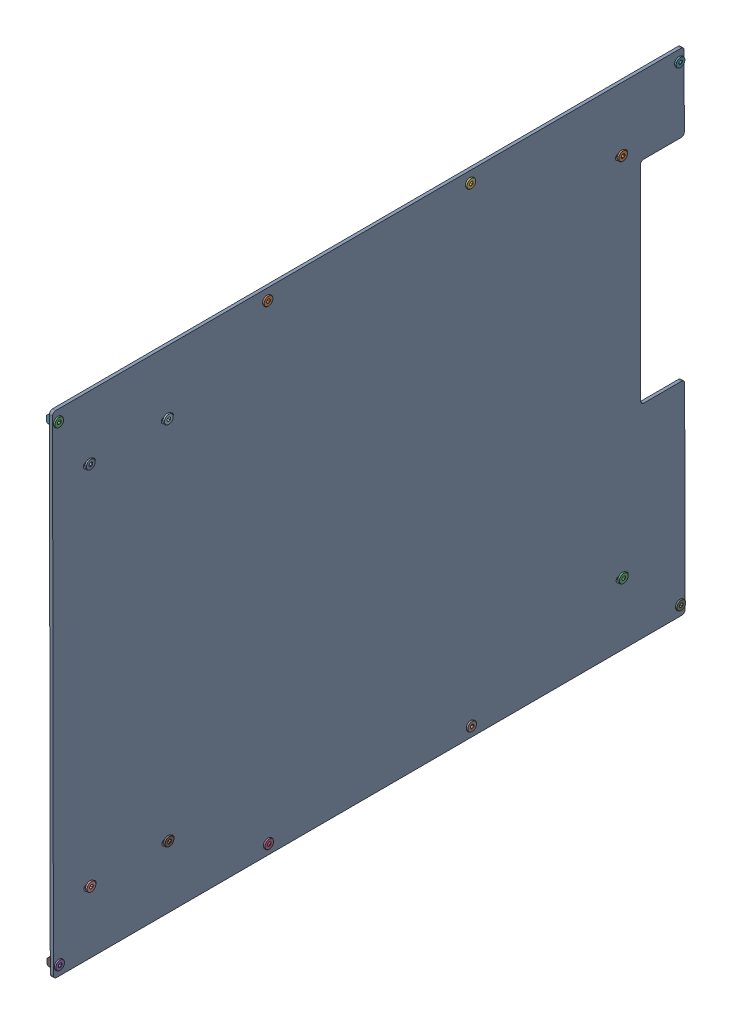
SolidWorks assembly right_side_panel_assembly, configuration Default. Lengths in mm.
Overall size (9.62 471.07 605.65).
29 component instances, 3 part files, 0 mates.
Components (placement in the parent):
- side_plates_ethernet side-1: side_plates_ethernet side [Default] at (353.1615 3.567 528.4447) x (0 0.00178 -0.999998) z (1 0 0) size (604 470 3)
- m5_low_profile_screw_template_M5 x 8-1: m5_low_profile_screw_template_M5 x 8 [Default] at (348.1615 463.9311 324.2637) x (-1 0 0) z (0 -0.182924 -0.983127) size (9.62 9 9)
- m5_low_profile_screw_template_M5 x 8-2: m5_low_profile_screw_template_M5 x 8 [Default] at (348.1615 463.5751 524.2634) x (-1 0 0) z (0 0.043669 0.999046) size (9.62 9 9)
- m5_low_profile_screw_template_M5 x 8-3: m5_low_profile_screw_template_M5 x 8 [Default] at (348.1615 13.9318 323.4628) x (-1 0 0) z (0 0.609329 -0.792918) size (9.62 9 9)
- m5_low_profile_screw_template_M5 x 8-4: m5_low_profile_screw_template_M5 x 8 [Default] at (348.1615 13.5759 523.4625) x (-1 0 0) z (0 0.039718 0.999211) size (9.62 9 9)
- m5_low_profile_screw_template_M5 x 8-5: m5_low_profile_screw_template_M5 x 8 [Default] at (348.1615 464.2764 130.264) x (-1 0 0) z (0 0.965121 0.261804) size (9.62 9 9)
- m5_low_profile_screw_template_M5 x 8-6: m5_low_profile_screw_template_M5 x 8 [Default] at (348.1615 464.6324 -69.7356) x (-1 0 0) z (0 -0.990373 0.138424) size (9.62 9 9)
- m5_low_profile_screw_template_M5 x 8-7: m5_low_profile_screw_template_M5 x 8 [Default] at (348.1615 14.2771 129.4631) x (-1 0 0) z (0 -0.004546 0.99999) size (9.62 9 9)
- m5_low_profile_screw_template_M5 x 8-8: m5_low_profile_screw_template_M5 x 8 [Default] at (348.1615 14.6331 -70.5366) x (-1 0 0) z (0 0.364215 0.931315) size (9.62 9 9)
- m5_low_profile_screw_template_M5 x 8-9: m5_low_profile_screw_template_M5 x 8 [Default] at (348.1615 63.6292 493.5515) x (-1 0 0) z (0 0.249598 0.96835) size (9.62 9 9)
- m5_low_profile_screw_template_M5 x 8-10: m5_low_profile_screw_template_M5 x 8 [Default] at (348.1615 63.762 418.9266) x (-1 0 0) z (0 0.548773 -0.835971) size (9.62 9 9)
- m5_low_profile_screw_template_M5 x 8-11: m5_low_profile_screw_template_M5 x 8 [Default] at (348.1615 413.7614 419.5496) x (-1 0 0) z (0 0.23279 0.972527) size (9.62 9 9)
- m5_low_profile_screw_template_M5 x 8-12: m5_low_profile_screw_template_M5 x 8 [Default] at (348.1615 413.6286 494.1745) x (-1 0 0) z (0 -0.355999 0.934486) size (9.62 9 9)
- m5_low_profile_screw_template_M5 x 8-13: m5_low_profile_screw_template_M5 x 8 [Default] at (348.1615 414.5346 -14.8247) x (-1 0 0) z (0 -0.12553 0.99209) size (9.62 9 9)
- m5_low_profile_screw_template_M5 x 8-14: m5_low_profile_screw_template_M5 x 8 [Default] at (348.1615 64.5351 -15.4477) x (-1 0 0) z (0 -0.733147 0.68007) size (9.62 9 9)
- m5_locking_t_nut_20x20_generic-1: m5_locking_t_nut_20x20_generic [Default] at (348.1615 464.6377 -72.7356) x (0 -0.999998 -0.00178) z (0 -0.00178 0.999998) size (10 4.5 6)
- m5_locking_t_nut_20x20_generic-2: m5_locking_t_nut_20x20_generic [Default] at (348.1615 464.2818 127.2641) x (0 -0.999998 -0.00178) z (0 -0.00178 0.999998) size (10 4.5 6)
- m5_locking_t_nut_20x20_generic-3: m5_locking_t_nut_20x20_generic [Default] at (348.1615 463.9365 321.2637) x (0 -0.999998 -0.00178) z (0 -0.00178 0.999998) size (10 4.5 6)
- m5_locking_t_nut_20x20_generic-4: m5_locking_t_nut_20x20_generic [Default] at (348.1615 463.5805 521.2634) x (0 -0.999998 -0.00178) z (0 -0.00178 0.999998) size (10 4.5 6)
- m5_locking_t_nut_20x20_generic-5: m5_locking_t_nut_20x20_generic [Default] at (348.1615 14.6384 -73.5366) x (0 -0.999998 -0.00178) z (0 -0.00178 0.999998) size (10 4.5 6)
- m5_locking_t_nut_20x20_generic-6: m5_locking_t_nut_20x20_generic [Default] at (348.1615 14.2825 126.4631) x (0 -0.999998 -0.00178) z (0 -0.00178 0.999998) size (10 4.5 6)
- m5_locking_t_nut_20x20_generic-7: m5_locking_t_nut_20x20_generic [Default] at (348.1615 13.9372 320.4628) x (0 -0.999998 -0.00178) z (0 -0.00178 0.999998) size (10 4.5 6)
- m5_locking_t_nut_20x20_generic-8: m5_locking_t_nut_20x20_generic [Default] at (348.1615 13.5812 520.4625) x (0 -0.999998 -0.00178) z (0 -0.00178 0.999998) size (10 4.5 6)
- m5_locking_t_nut_20x20_generic-9: m5_locking_t_nut_20x20_generic [Default] at (348.1615 66.6292 493.5569) x (0 0.00178 -0.999998) z (0 -0.999998 -0.00178) size (10 4.5 6)
- m5_locking_t_nut_20x20_generic-10: m5_locking_t_nut_20x20_generic [Default] at (348.1615 66.762 418.932) x (0 0.00178 -0.999998) z (0 -0.999998 -0.00178) size (10 4.5 6)
- m5_locking_t_nut_20x20_generic-11: m5_locking_t_nut_20x20_generic [Default] at (348.1615 67.5351 -15.4423) x (0 0.00178 -0.999998) z (0 -0.999998 -0.00178) size (10 4.5 6)
- m5_locking_t_nut_20x20_generic-12: m5_locking_t_nut_20x20_generic [Default] at (348.1615 417.5346 -14.8194) x (0 0.00178 -0.999998) z (0 -0.999998 -0.00178) size (10 4.5 6)
- m5_locking_t_nut_20x20_generic-13: m5_locking_t_nut_20x20_generic [Default] at (348.1615 410.6286 494.1691) x (0 -0.00178 0.999998) z (0 0.999998 0.00178) size (10 4.5 6)
- m5_locking_t_nut_20x20_generic-14: m5_locking_t_nut_20x20_generic [Default] at (348.1615 410.7614 419.5443) x (0 -0.00178 0.999998) z (0 0.999998 0.00178) size (10 4.5 6)
